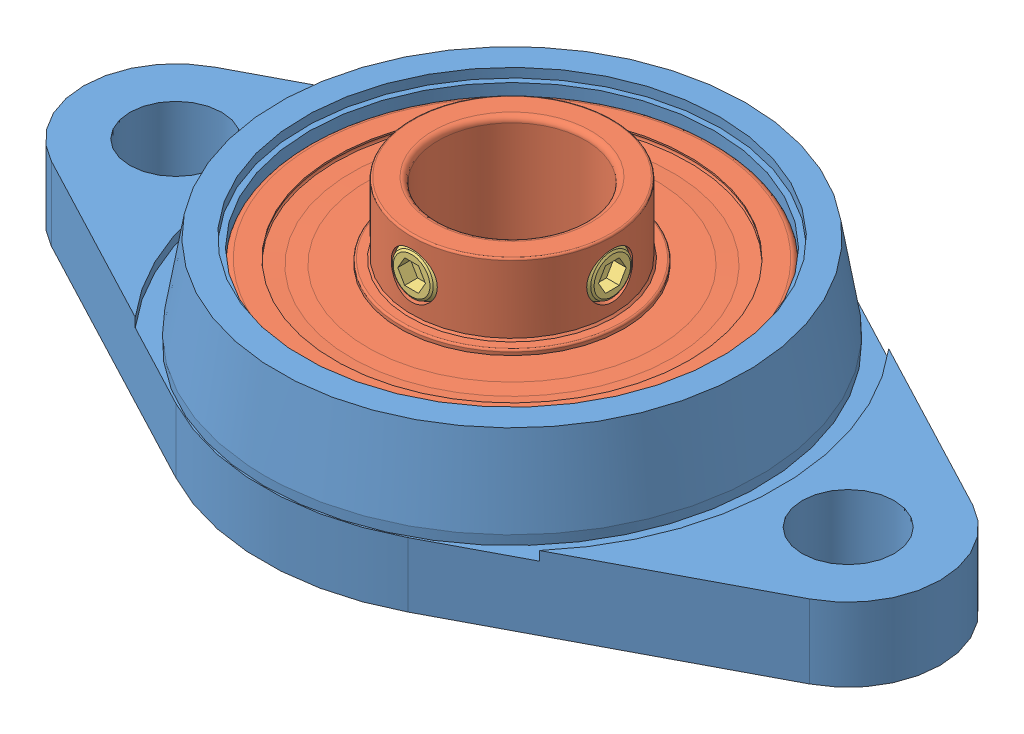
SolidWorks assembly KFL08, configuration Varsayılan. Lengths in mm.
Overall size (46.5 11.35 27).
4 component instances, 3 part files, 10 mates.
Components (placement in the parent):
- FLANGE^KFL08-1: FLANGE^KFL08 [Default] at origin size (46.5 8.5 27) (virtual)
- BEARING^KFL08-1: BEARING^KFL08 [Default] at (0 4 0) x (1 0 0) z (0 -1 0) size (22 22 10.85) (virtual)
- socket set screw cone point_am-1: socket set screw cone point_am [B18.3.6M - M2.5 x 0.45 x 2 Hex Socket Cone Pt. SS --S] at (0 9.425 5.45) x (0 0 -1) z (1 0 0) size (2 2.5 2.5)
- socket set screw cone point_am-2: socket set screw cone point_am [B18.3.6M - M2.5 x 0.45 x 2 Hex Socket Cone Pt. SS --S] at (5.45 9.425 0) x (-1 0 0) z (0 0 -1) size (2 2.5 2.5)
Mates (geometry in assembly coordinates):
- Concentric1: concentric: cylinder of FLANGE^KFL08-1 through (0 4 0) axis (0 -1 0) radius 11; cylinder of BEARING^KFL08-1 through (0 0.5 0) axis (0 -1 0) radius 11
- Coincident1: coincident: plane of FLANGE^KFL08-1 through (0 0.5 0) normal (0 -1 0); plane of BEARING^KFL08-1 through (0 0.5 9.6) normal (0 -1 0)
- Coincident2: coordinate: point of FLANGE^KFL08-1; point of assembly
- Coincident3: coincident: plane of FLANGE^KFL08-1 through (0 0 0) normal (1 0 0); plane of BEARING^KFL08-1 through (0 4 0) normal (1 0 0)
- Concentric2: concentric: cylinder of BEARING^KFL08-1 through (0 9.425 5.45) axis (0 0 1) radius 1.25; cylinder of socket set screw cone point_am-1 through (0 9.425 18.15) axis (0 0 1) radius 1.25
- Tangent1: tangent: cylinder of BEARING^KFL08-1 through (0 0.5 0) axis (0 -1 0) radius 5.45; plane of socket set screw cone point_am-1 through (0 9.425 5.45) normal (0 0 1)
- Concentric3: concentric: cylinder of BEARING^KFL08-1 through (5.45 9.425 0) axis (1 0 0) radius 1.25; cylinder of socket set screw cone point_am-2 through (18.15 9.425 0) axis (1 0 0) radius 1.25
- Tangent3: tangent: cylinder of BEARING^KFL08-1 through (0 0.5 0) axis (0 -1 0) radius 5.45; plane of socket set screw cone point_am-2 through (5.45 9.425 0) normal (1 0 0)
- Parallel1: parallel: plane of socket set screw cone point_am-1 through (0 9.425 5.45) normal (0 1 0); plane of assembly through (0 0 0) normal (0 1 0)
- Parallel2: parallel: plane of socket set screw cone point_am-2 through (5.45 9.425 0) normal (0 1 0); plane of assembly through (0 0 0) normal (0 1 0)
